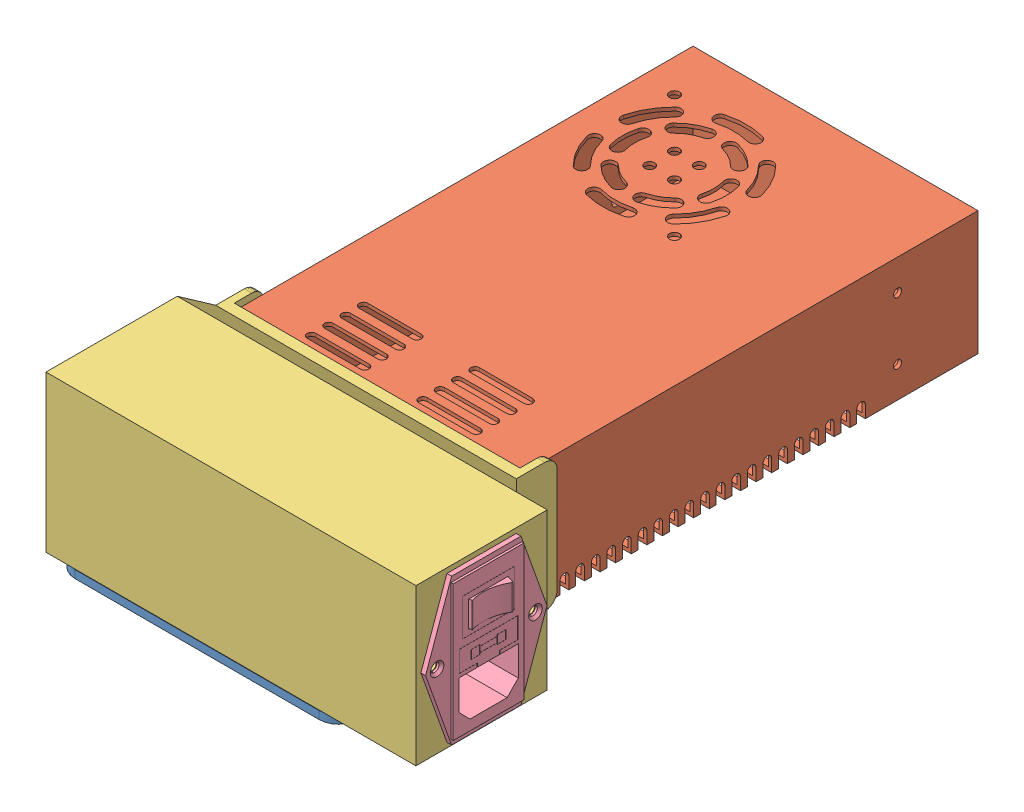
SolidWorks assembly Power Supply ASMB, configuration Default. Lengths in mm.
Overall size (171.65 66.67 258).
4 component instances, 4 part files, 10 mates.
Components (placement in the parent):
- Power Supply Mount-1: Power Supply Mount [Default] at origin size (154.5 3.17 105.18)
- Genssi 24V 14.5A 350W-1: Genssi 24V 14.5A 350W [Default] at (0 3.175 0) x (0 0 -1) z (1 0 0) size (215 50 115)
- Power Supply Cover-1: Power Supply Cover [Default] at (-60.65 28.175 86.5) x (0 -1 0) z (0 0 1) size (63 152.3 85)
- Amazon_Electrical_Fused_Plug-1: Amazon_Electrical_Fused_Plug [Default] at (88.65 35.175 124) x (0 0 1) z (1 0 0) size (49 59 24.75)
Mates (geometry in assembly coordinates):
- Concentric1: concentric aligned: cylinder of Power Supply Mount-1 through (-25 3.175 75) axis (0 -1 0) radius 2.1; cylinder of Genssi 24V 14.5A 350W-1 through (-25 3.175 75) axis (0 -1 0) radius 1.65
- Coincident1: coincident anti-aligned: plane of Power Supply Mount-1 through (0 3.175 0) normal (0 1 0); plane of Genssi 24V 14.5A 350W-1 through (0 3.175 0) normal (0 -1 0)
- Concentric2: concentric aligned: cylinder of Power Supply Mount-1 through (25 3.175 75) axis (0 -1 0) radius 2.1; cylinder of Genssi 24V 14.5A 350W-1 through (25 3.175 75) axis (0 -1 0) radius 1.65
- Concentric3: concentric aligned: cylinder of Genssi 24V 14.5A 350W-1 through (-57.5 15.675 75) axis (-1 0 0) radius 1.65; cylinder of Power Supply Cover-1 through (66.5897 15.675 75) axis (-1 0 0) radius 2.1
- Concentric4: concentric aligned: cylinder of Genssi 24V 14.5A 350W-1 through (-57.5 40.675 75) axis (-1 0 0) radius 1.65; cylinder of Power Supply Cover-1 through (66.5897 40.675 75) axis (-1 0 0) radius 2.1
- Distance1: distance = 0.15 mm anti-aligned: plane of Genssi 24V 14.5A 350W-1 through (-57.5 53.175 107.5) normal (-1 0 0); plane of Power Supply Cover-1 through (-57.65 28.175 86.5) normal (1 0 0)
- Coincident3: coincident anti-aligned: plane of Power Supply Cover-1 through (88.65 28.175 86.5) normal (1 0 0); plane of Amazon_Electrical_Fused_Plug-1 through (88.65 35.175 124) normal (-1 0 0)
- Coincident6: coincident: plane of Amazon_Electrical_Fused_Plug-1; point of assembly
- Coincident7: coincident: plane of Amazon_Electrical_Fused_Plug-1; point of assembly
- Parallel1: parallel aligned: plane of Power Supply Cover-1 through (60.65 66.675 86.5) normal (0 1 0); plane of Amazon_Electrical_Fused_Plug-1 through (90.55 64.675 110) normal (0 1 0)
